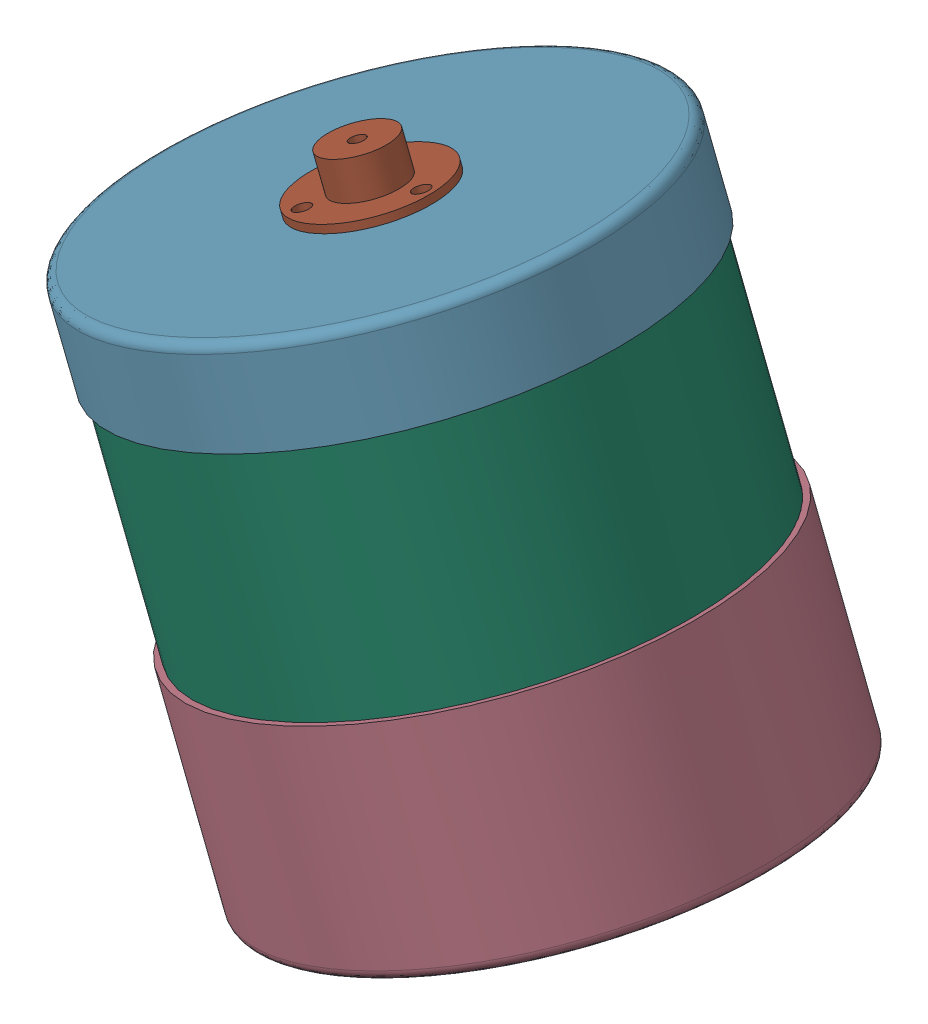
SolidWorks assembly Assem3, configuration Default. Lengths in mm.
Overall size (263.97 234.42 224.68).
30 component instances, 16 part files, 73 mates.
Components (placement in the parent):
- Part6-1: Part6 [Default] at (36.0721 -6.8818 42.4182) x (0.566675 0.224157 -0.792864) z (-0.751204 -0.254761 -0.608925) size (150 30 150)
- Part2-1: Part2 [Default] at (4.9044 -18.2993 50.3372) x (-0.566675 -0.224157 0.792864) z (0.338486 -0.940665 -0.024021) size (23 30 75)
- Part2-2: Part2 [Default] at (59.7422 0.2982 94.7887) x (-0.566675 -0.224157 0.792864) z (0.338486 -0.940665 -0.024021) size (23 30 75)
- Part2-3: Part2 [Default] at (89.776 12.1785 52.7669) x (-0.566675 -0.224157 0.792864) z (0.338486 -0.940665 -0.024021) size (23 30 75)
- Part2-4: Part2 [Default] at (34.9381 -6.419 8.3154) x (-0.566675 -0.224157 0.792864) z (0.338486 -0.940665 -0.024021) size (23 30 75)
- Part7-1: Part7 [Default] at (30.8691 42.7035 88.0332) x (0.751204 0.254761 0.608925) z (0.338486 -0.940665 -0.024021) size (27 7 49.09)
- Part7-2: Part7 [Default] at (7.765 36.6587 -0.8187) x (-0.751204 -0.254761 -0.608925) z (0.338486 -0.940665 -0.024021) size (27 7 49.09)
- Part7-3: Part7 [Default] at (62.6029 55.2563 43.6328) x (-0.751204 -0.254761 -0.608925) z (0.338486 -0.940665 -0.024021) size (27 7 49.09)
- Part7-4: Part7 [Default] at (-23.9688 24.1059 43.5816) x (0.751204 0.254761 0.608925) z (0.338486 -0.940665 -0.024021) size (27 7 49.09)
- Part12-1: Part12 [Default] at (79.6031 61.981 19.8469) x (-0.768593 0.49055 -0.410641) z (0.296891 0.842089 0.450268) size (8 96 8)
- Part3-1: Part3 [Default] at (72.7956 65.5596 15.9931) x (-0.646652 -0.475345 -0.596563) z (-0.510608 0.850765 -0.124414) size (34 20 14.01)
- Part1-1: Part1 [Default] at (45.2725 49.828 77.6393) x (0.510608 -0.850765 0.124414) z (0.646652 0.475345 0.596563) size (18 45 20)
- Part7-5: Part7 [Default] at (36.0721 -6.8818 42.4182) x (0.751204 0.254761 0.608925) z (-0.566675 -0.224157 0.792864) size (27 7 49.09)
- Part5-1: Part5 [Default] at (32.2222 3.8172 42.6914) x (0.751204 0.254761 0.608925) z (-0.566675 -0.224157 0.792864) size (30 58 30)
- Part11-1: Part11 [Default] at (3.916 82.4813 44.7002) x (0.928405 0.329698 0.171358) z (0.338486 -0.940665 -0.024021) size (8.23 9.24 95.88)
- Part7-6: Part7 [Default] at (30.9062 34.4588 31.495) x (-0.751204 -0.254761 -0.608925) z (0.338486 -0.940665 -0.024021) size (27 7 49.09)
- Part7-7: Part7 [Default] at (13.906 27.7341 55.281) x (0.751204 0.254761 0.608925) z (0.338486 -0.940665 -0.024021) size (27 7 49.09)
- Part4-1: Part4 [Default] at (56.6655 34.1236 23.9553) x (-0.566675 -0.224157 0.792864) z (0.510608 -0.850765 0.124414) size (55 24 20.86)
- Part3-2: Part3 [Default] at (-24.5579 15.1388 53.2379) x (0.81087 0.019007 0.584917) z (0.146183 -0.974368 -0.170992) size (34 20 14.01)
- Part12-2: Part12 [Default] at (13.4318 38.9003 -8.7474) x (-0.083667 0.972963 0.215276) z (0.819683 -0.055655 0.570108) size (8 96 8)
- Part4-2: Part4 [Default] at (10.1923 35.5466 80.6911) x (0.566675 0.224157 -0.792864) z (-0.146183 0.974368 0.170992) size (55 24 20.86)
- Part1-2: Part1 [Default] at (-19.0393 28.0172 25.5081) x (-0.146183 0.974368 0.170992) z (-0.81087 -0.019007 -0.584917) size (18 45 20)
- Part16-1: Part16 [Default] at (5.6084 77.778 44.5801) x (0.907225 0.319465 0.273653) z (-0.338486 0.940665 0.024021) size (14 14 22)
- SlipRing-1: SlipRing [Default] at (1.6143 88.8779 44.8635) x (-0.338486 0.940665 0.024021) z (0.421071 0.174247 -0.890133) size (19 44.5 44.5)
- Part18-1: Part18 [Default] at (53.3349 -54.8557 41.1931) x (0.647803 0.251467 -0.719108) z (0.68248 0.227847 0.694483) size (138 21 138)
- Bottom_part-1: Bottom_part [Default] at (59.0891 -70.847 40.7847) x (-0.338486 0.940665 0.024021) z (-0.388736 -0.163038 0.906809) size (68 162 162)
- Top part-1: Top part [Default] at (1.6143 88.8779 44.8635) x (-0.518227 -0.165048 -0.839166) z (0.338486 -0.940665 -0.024021) size (162 162 29.5)
- Mirror-1: Mirror [Default] at (39.3554 -16.0063 42.1852) x (0.940962 0.338486 0.00419) z (0.00419 -0.024021 0.999703) size (158 92 158)
- Part19-2: Part19 [Default] at (6.8631 20.6102 89.8545) x (-0.160524 -0.953915 0.253531) z (0.56278 -0.299474 -0.77045) size (8 40 8)
- Part19-3: Part19 [Default] at (66.1761 54.0361 20.6166) x (0.710148 -0.660656 -0.243359) z (0.278443 0.581017 -0.76478) size (8 40 8)
Mates (geometry in assembly coordinates):
- Coincident3: coincident anti-aligned: plane of Part6-1 through (36.0721 -6.8818 42.4182) normal (-0.338486 0.940665 0.024021); plane of Part2-1 through (-11.115 -23.3644 22.9515) normal (0.338486 -0.940665 -0.024021)
- Concentric5: concentric anti-aligned: cylinder of Part6-1 through (-0.789 -51.6861 28.6309) axis (-0.338486 0.940665 0.024021) radius 1.5; cylinder of Part2-1 through (-36.33 47.0838 31.1531) axis (0.338486 -0.940665 -0.024021) radius 1.5
- Concentric6: concentric anti-aligned: cylinder of Part6-1 through (15.7375 -46.0813 42.0272) axis (-0.338486 0.940665 0.024021) radius 1.5; cylinder of Part2-1 through (-19.8035 52.6885 44.5494) axis (0.338486 -0.940665 -0.024021) radius 1.5
- Coincident4: coincident anti-aligned: plane of Part6-1 through (36.0721 -6.8818 42.4182) normal (-0.338486 0.940665 0.024021); plane of Part2-2 through (43.7229 -4.7668 67.403) normal (0.338486 -0.940665 -0.024021)
- Concentric7: concentric anti-aligned: cylinder of Part6-1 through (54.0489 -33.0885 73.0824) axis (-0.338486 0.940665 0.024021) radius 1.5; cylinder of Part2-2 through (18.5079 65.6813 75.6046) axis (0.338486 -0.940665 -0.024021) radius 1.5
- Concentric8: concentric anti-aligned: cylinder of Part6-1 through (70.5754 -27.4838 86.4787) axis (-0.338486 0.940665 0.024021) radius 1.5; cylinder of Part2-2 through (35.0344 71.286 89.001) axis (0.338486 -0.940665 -0.024021) radius 1.5
- Coincident5: coincident anti-aligned: plane of Part6-1 through (36.0721 -6.8818 42.4182) normal (-0.338486 0.940665 0.024021); plane of Part2-4 through (18.9188 -11.484 -19.0703) normal (0.338486 -0.940665 -0.024021)
- Concentric9: concentric anti-aligned: cylinder of Part6-1 through (29.2448 -39.8057 -13.3909) axis (-0.338486 0.940665 0.024021) radius 1.5; cylinder of Part2-4 through (-6.2962 58.9641 -10.8687) axis (0.338486 -0.940665 -0.024021) radius 1.5
- Concentric10: concentric anti-aligned: cylinder of Part6-1 through (38.4045 -37.115 10.3127) axis (-0.338486 0.940665 0.024021) radius 1.5; cylinder of Part2-4 through (2.8635 61.6548 12.8349) axis (0.338486 -0.940665 -0.024021) radius 1.5
- Coincident6: coincident anti-aligned: plane of Part6-1 through (36.0721 -6.8818 42.4182) normal (-0.338486 0.940665 0.024021); plane of Part2-3 through (73.7566 7.1135 25.3812) normal (0.338486 -0.940665 -0.024021)
- Concentric11: concentric anti-aligned: cylinder of Part6-1 through (84.0826 -21.2082 31.0606) axis (-0.338486 0.940665 0.024021) radius 1.5; cylinder of Part2-3 through (48.5416 77.5616 33.5828) axis (0.338486 -0.940665 -0.024021) radius 1.5
- Concentric12: concentric anti-aligned: cylinder of Part6-1 through (93.2424 -18.5175 54.7642) axis (-0.338486 0.940665 0.024021) radius 1.5; cylinder of Part2-3 through (57.7014 80.2523 57.2864) axis (0.338486 -0.940665 -0.024021) radius 1.5
- Coincident7: coincident anti-aligned: plane of Part2-4 through (11.8981 -9.9629 -11.0456) normal (0.566675 0.224157 -0.792864); plane of Part7-2 through (7.765 36.6587 -0.8187) normal (-0.566675 -0.224157 0.792864)
- Concentric13: concentric aligned: cylinder of Part2-4 through (-5.6945 50.6766 9.9209) axis (0.566675 0.224157 -0.792864) radius 1.5; cylinder of Part7-2 through (1.6723 53.5907 -0.3864) axis (0.566675 0.224157 -0.792864) radius 2
- Concentric14: concentric aligned: cylinder of Part2-4 through (6.491 16.8127 9.0561) axis (0.566675 0.224157 -0.792864) radius 1.5; cylinder of Part7-2 through (13.8578 19.7268 -1.2511) axis (0.566675 0.224157 -0.792864) radius 2
- Coincident8: coincident anti-aligned: plane of Part2-3 through (66.7359 8.6346 33.4059) normal (0.566675 0.224157 -0.792864); plane of Part7-3 through (62.6029 55.2563 43.6328) normal (-0.566675 -0.224157 0.792864)
- Concentric15: concentric aligned: cylinder of Part2-3 through (49.1434 69.2742 54.3724) axis (0.566675 0.224157 -0.792864) radius 1.5; cylinder of Part7-3 through (56.5102 72.1882 44.0652) axis (0.566675 0.224157 -0.792864) radius 2
- Concentric16: concentric aligned: cylinder of Part2-3 through (61.3289 35.4103 53.5076) axis (0.566675 0.224157 -0.792864) radius 1.5; cylinder of Part7-3 through (68.6956 38.3243 43.2004) axis (0.566675 0.224157 -0.792864) radius 2
- Coincident10: coincident anti-aligned: plane of Part2-1 through (-19.8357 -22.5157 33.3548) normal (-0.566675 -0.224157 0.792864); plane of Part7-4 through (-23.9688 24.1059 43.5816) normal (0.566675 0.224157 -0.792864)
- Concentric17: concentric anti-aligned: cylinder of Part2-1 through (-23.5428 4.9324 51.0779) axis (0.566675 0.224157 -0.792864) radius 1.5; cylinder of Part7-4 through (-17.876 7.1739 43.1493) axis (-0.566675 -0.224157 0.792864) radius 2
- Concentric18: concentric anti-aligned: cylinder of Part2-1 through (-35.7283 38.7963 51.9427) axis (0.566675 0.224157 -0.792864) radius 1.5; cylinder of Part7-4 through (-30.0615 41.0379 44.014) axis (-0.566675 -0.224157 0.792864) radius 2
- Coincident11: coincident anti-aligned: plane of Part2-2 through (35.0022 -3.9182 77.8063) normal (-0.566675 -0.224157 0.792864); plane of Part7-1 through (30.8691 42.7035 88.0332) normal (0.566675 0.224157 -0.792864)
- Concentric19: concentric anti-aligned: cylinder of Part2-2 through (19.1096 57.3939 96.3942) axis (0.566675 0.224157 -0.792864) radius 1.5; cylinder of Part7-1 through (24.7764 59.6354 88.4655) axis (-0.566675 -0.224157 0.792864) radius 2
- Concentric20: concentric anti-aligned: cylinder of Part2-2 through (31.2951 23.5299 95.5294) axis (0.566675 0.224157 -0.792864) radius 1.5; cylinder of Part7-1 through (36.9619 25.7715 87.6008) axis (-0.566675 -0.224157 0.792864) radius 2
- Concentric22: concentric anti-aligned: cylinder of Part12-1 through (25.2024 40.4619 95.9618) axis (0.566675 0.224157 -0.792864) radius 4; cylinder of Part3-1 through (79.6031 61.981 19.8469) axis (-0.566675 -0.224157 0.792864) radius 4
- Concentric23: concentric aligned: cylinder of Part12-1 through (25.2024 40.4619 95.9618) axis (0.566675 0.224157 -0.792864) radius 4; cylinder of Part1-1 through (41.0693 46.7383 73.7616) axis (0.566675 0.224157 -0.792864) radius 4.15
- Coincident13: coincident anti-aligned: plane of Part6-1 through (36.0721 -6.8818 42.4182) normal (-0.338486 0.940665 0.024021); plane of Part7-5 through (36.0721 -6.8818 42.4182) normal (0.338486 -0.940665 -0.024021)
- Concentric24: concentric aligned: cylinder of Part6-1 through (56.4268 -31.0669 27.426) axis (-0.338486 0.940665 0.024021) radius 2; cylinder of Part7-5 through (46.2723 -2.847 28.1466) axis (-0.338486 0.940665 0.024021) radius 2
- Concentric25: concentric aligned: cylinder of Part6-1 through (36.0265 -39.1366 55.9691) axis (-0.338486 0.940665 0.024021) radius 2; cylinder of Part7-5 through (25.872 -10.9166 56.6897) axis (-0.338486 0.940665 0.024021) radius 2
- Concentric26: concentric aligned: cylinder of Part7-5 through (36.0721 -6.8818 42.4182) axis (-0.338486 0.940665 0.024021) radius 4; cylinder of Part5-1 through (15.9749 48.9691 43.8444) axis (-0.338486 0.940665 0.024021) radius 5.5
- Parallel3: parallel aligned: plane of Part2-4 through (11.8981 -9.9629 -11.0456) normal (0.566675 0.224157 -0.792864); plane of Part5-1 through (9.8221 57.9167 23.0578) normal (0.566675 0.224157 -0.792864)
- Concentric27: concentric aligned: cylinder of Part5-1 through (15.9749 48.9691 43.8444) axis (-0.338486 0.940665 0.024021) radius 5.5; cylinder of Part11-1 through (36.0721 -6.8818 42.4182) axis (-0.338486 0.940665 0.024021) radius 4
- Coincident14: coincident anti-aligned: plane of Part6-1 through (36.0721 -6.8818 42.4182) normal (-0.338486 0.940665 0.024021); plane of Part11-1 through (36.0721 -6.8818 42.4182) normal (0.338486 -0.940665 -0.024021)
- Coincident15: coincident anti-aligned: plane of Part5-1 through (9.8221 57.9167 23.0578) normal (0.566675 0.224157 -0.792864); plane of Part7-6 through (30.9062 34.4588 31.495) normal (-0.566675 -0.224157 0.792864)
- Concentric28: concentric aligned: cylinder of Part5-1 through (20.2801 49.5975 38.2703) axis (0.566675 0.224157 -0.792864) radius 1.25; cylinder of Part7-6 through (24.8135 51.3908 31.9274) axis (0.566675 0.224157 -0.792864) radius 2
- Concentric29: concentric aligned: cylinder of Part5-1 through (32.4656 15.7336 37.4056) axis (0.566675 0.224157 -0.792864) radius 1.25; cylinder of Part7-6 through (36.999 17.5269 31.0626) axis (0.566675 0.224157 -0.792864) radius 2
- Coincident16: coincident anti-aligned: plane of Part5-1 through (-7.1781 51.192 46.8437) normal (-0.566675 -0.224157 0.792864); plane of Part7-7 through (13.906 27.7341 55.281) normal (0.566675 0.224157 -0.792864)
- Concentric30: concentric aligned: cylinder of Part5-1 through (12.3467 46.4593 49.3704) axis (-0.566675 -0.224157 0.792864) radius 1.25; cylinder of Part7-7 through (7.8133 44.6661 55.7133) axis (-0.566675 -0.224157 0.792864) radius 2
- Concentric31: concentric aligned: cylinder of Part5-1 through (24.5321 12.5954 48.5057) axis (-0.566675 -0.224157 0.792864) radius 1.25; cylinder of Part7-7 through (19.9988 10.8022 54.8486) axis (-0.566675 -0.224157 0.792864) radius 2
- Concentric32: concentric aligned: cylinder of Part7-6 through (30.9062 34.4588 31.495) axis (0.566675 0.224157 -0.792864) radius 4; cylinder of Part4-1 through (32.0396 34.9072 29.9093) axis (0.566675 0.224157 -0.792864) radius 4
- Concentric34: concentric anti-aligned: cylinder of Part3-1 through (66.1761 54.0361 20.6166) axis (-0.646652 -0.475345 -0.596563) radius 4; cylinder of Part4-1 through (41.8467 36.1519 -1.8282) axis (0.646652 0.475345 0.596563) radius 7.5
- Concentric35: concentric aligned: cylinder of Part7-2 through (7.765 36.6587 -0.8187) axis (0.566675 0.224157 -0.792864) radius 4; cylinder of Part12-2 through (-40.969 17.3812 67.3676) axis (0.566675 0.224157 -0.792864) radius 4
- Concentric36: concentric anti-aligned: cylinder of Part3-2 through (-29.6355 21.8643 51.5103) axis (-0.566675 -0.224157 0.792864) radius 4; cylinder of Part12-2 through (-40.969 17.3812 67.3676) axis (0.566675 0.224157 -0.792864) radius 4
- Coincident18: coincident aligned: plane of Part3-2 through (-35.8914 10.6557 69.0952) normal (-0.566675 -0.224157 0.792864); plane of Part12-2 through (-40.969 17.3812 67.3676) normal (-0.566675 -0.224157 0.792864)
- Concentric37: concentric aligned: cylinder of Part7-7 through (13.906 27.7341 55.281) axis (-0.566675 -0.224157 0.792864) radius 4; cylinder of Part4-2 through (12.7727 27.2858 56.8667) axis (-0.566675 -0.224157 0.792864) radius 4
- Concentric38: concentric aligned: cylinder of Part3-2 through (-25.5717 19.8499 66.4578) axis (0.81087 0.019007 0.584917) radius 4; cylinder of Part4-2 through (-14.5247 20.1089 74.4265) axis (0.81087 0.019007 0.584917) radius 7.5
- Concentric39: concentric aligned: cylinder of Part12-2 through (-40.969 17.3812 67.3676) axis (0.566675 0.224157 -0.792864) radius 4; cylinder of Part1-2 through (-13.7686 28.1407 29.3101) axis (0.566675 0.224157 -0.792864) radius 4.15
- Distance7: distance = 3 mm aligned: plane of Part12-2 through (13.4318 38.9003 -8.7474) normal (0.566675 0.224157 -0.792864); plane of Part7-2 through (11.7317 38.2278 -6.3688) normal (0.566675 0.224157 -0.792864)
- Distance8: distance = 2.5 mm anti-aligned: plane of Part1-1 through (34.8869 55.6336 87.6235) normal (-0.566675 -0.224157 0.792864); plane of Part2-2 through (36.7022 -3.2457 75.4277) normal (0.566675 0.224157 -0.792864)
- Concentric41: concentric anti-aligned: cylinder of Part11-1 through (36.0721 -6.8818 42.4182) axis (-0.338486 0.940665 0.024021) radius 4; cylinder of Part16-1 through (-1.8383 98.4726 45.1085) axis (0.338486 -0.940665 -0.024021) radius 2.4
- Coincident19: coincident anti-aligned: plane of Part11-1 through (3.916 82.4813 44.7002) normal (-0.338486 0.940665 0.024021); plane of Part16-1 through (3.916 82.4813 44.7002) normal (0.338486 -0.940665 -0.024021)
- Concentric42: concentric aligned: cylinder of Part16-1 through (-1.8383 98.4726 45.1085) axis (0.338486 -0.940665 -0.024021) radius 2.4; cylinder of Part14-1 through (-3.1922 102.2353 45.2046) axis (0.338486 -0.940665 -0.024021) radius 2.5
- Coincident20: coincident anti-aligned: plane of Part16-1 through (3.239 84.3627 44.7482) normal (-0.338486 0.940665 0.024021); plane of Part14-1 through (3.239 84.3627 44.7482) normal (0.338486 -0.940665 -0.024021)
- Concentric43: concentric aligned: cylinder of Part6-1 through (46.2267 -35.1018 41.6975) axis (-0.338486 0.940665 0.024021) radius 14; cylinder of Part18-1 through (53.3349 -54.8557 41.1931) axis (-0.338486 0.940665 0.024021) radius 11.7
- Coincident21: coincident anti-aligned: plane of Part6-1 through (46.2267 -35.1018 41.6975) normal (0.338486 -0.940665 -0.024021); plane of Part18-1 through (46.2267 -35.1018 41.6975) normal (-0.338486 0.940665 0.024021)
- Concentric44: concentric aligned: cylinder of Part18-1 through (46.2267 -35.1018 41.6975) axis (0.338486 -0.940665 -0.024021) radius 32; cylinder of Part9-1 through (36.0721 -6.8818 42.4182) axis (0.338486 -0.940665 -0.024021) radius 77
- Coincident22: coincident anti-aligned: plane of Part18-1 through (54.3229 -54.4635 102.2023) normal (0.338486 -0.940665 -0.024021); plane of Part9-1 through (73.0203 -47.6411 98.5025) normal (-0.338486 0.940665 0.024021)
- Coincident23: coincident anti-aligned: plane of Part14-1 through (1.6143 88.8779 44.8635) normal (0.338486 -0.940665 -0.024021); plane of Part15-1 through (1.6143 88.8779 44.8635) normal (-0.338486 0.940665 0.024021)
- Concentric45: concentric anti-aligned: cylinder of Part14-1 through (18.005 94.7986 43.9741) axis (-0.338486 0.940665 0.024021) radius 2.7; cylinder of Part15-1 through (18.005 94.7986 43.9741) axis (0.338486 -0.940665 -0.024021) radius 2.6
- Concentric46: concentric anti-aligned: cylinder of Part14-1 through (-5.7334 85.8372 60.3963) axis (-0.338486 0.940665 0.024021) radius 2.7; cylinder of Part15-1 through (-5.7334 85.8372 60.3963) axis (0.338486 -0.940665 -0.024021) radius 2.6
- Concentric48: concentric aligned: cylinder of Part15-1 through (8.2147 70.5349 44.3951) axis (0.338486 -0.940665 -0.024021) radius 79; cylinder of Part17-1 through (8.2147 70.5349 44.3951) axis (0.338486 -0.940665 -0.024021) radius 79
- Coincident24: coincident anti-aligned: plane of Part15-1 through (8.2147 70.5349 44.3951) normal (0.338486 -0.940665 -0.024021); plane of Part17-1 through (8.2147 70.5349 44.3951) normal (-0.338486 0.940665 0.024021)
- Lock8: lock: 
- Parallel6: parallel aligned: plane of Part3-1 through (72.4552 69.1573 41.992) normal (0.646652 0.475345 0.596563); plane of Part1-1 through (46.5658 50.7787 78.8324) normal (0.646652 0.475345 0.596563)
- Lock9: lock: 
- Parallel9: parallel aligned: plane of Part3-2 through (-49.6762 10.3325 59.1516) normal (-0.81087 -0.019007 -0.584917); plane of Part1-2 through (-20.661 27.9792 24.3383) normal (-0.81087 -0.019007 -0.584917)
- Distance9: distance = 2.5 mm anti-aligned: plane of Part1-2 through (-26.4288 16.4079 32.7102) normal (-0.566675 -0.224157 0.792864); plane of Part2-1 through (-18.1357 -21.8433 30.9762) normal (0.566675 0.224157 -0.792864)
- Concentric51: concentric aligned: cylinder of Part4-2 through (-14.5247 20.1089 74.4265) axis (0.81087 0.019007 0.584917) radius 7.5; cylinder of Part19-2 through (-25.5717 19.8499 66.4578) axis (0.81087 0.019007 0.584917) radius 4
- Coincident26: coincident anti-aligned: plane of Part3-2 through (-18.8818 15.2718 57.3323) normal (0.81087 0.019007 0.584917); plane of Part19-2 through (-25.5717 19.8499 66.4578) normal (-0.81087 -0.019007 -0.584917)
- Concentric52: concentric aligned: cylinder of Part4-1 through (41.8467 36.1519 -1.8282) axis (0.646652 0.475345 0.596563) radius 7.5; cylinder of Part19-3 through (40.31 35.0223 -3.2459) axis (0.646652 0.475345 0.596563) radius 4
- Coincident27: coincident anti-aligned: plane of Part3-1 through (68.2691 62.2322 11.8172) normal (-0.646652 -0.475345 -0.596563); plane of Part19-3 through (66.1761 54.0361 20.6166) normal (0.646652 0.475345 0.596563)
- Lock11: lock: 
- Lock12: lock: 
